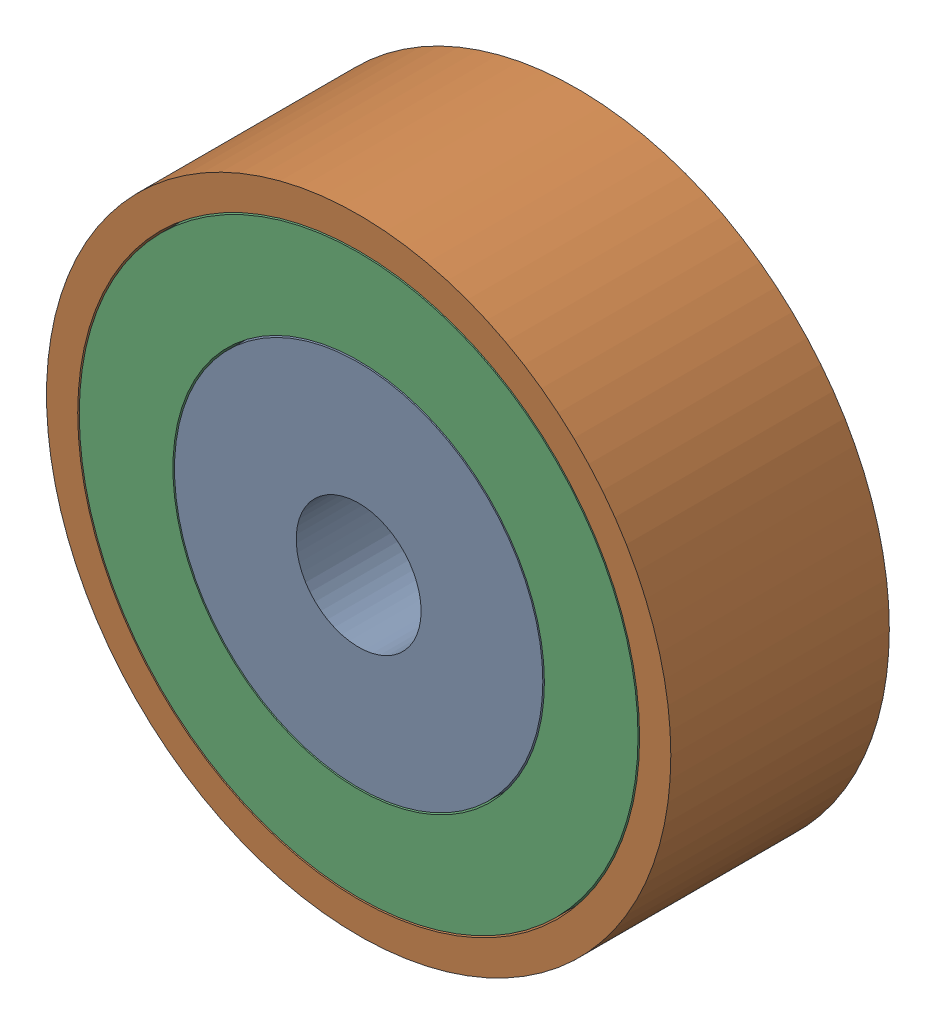
SolidWorks assembly 镜向轴承13, configuration 默认. Lengths in mm.
Overall size (20 20 7).
3 component instances, 3 part files, 4 mates.
Components (placement in the parent):
- 镜向轴承内圈-1: 镜向轴承内圈 [默认] at (-5.0655 0.8032 -6.5) size (11.8 11.8 7)
- 镜向轴承外圈-1: 镜向轴承外圈 [默认] at (-5.0655 0.8032 -6.5) size (20 20 7)
- 镜向轴承中圈-1: 镜向轴承中圈 [默认] at (-5.0655 0.8032 -6.5) size (17.9 17.9 7)
Mates (geometry in assembly coordinates):
- 重合1: coincident: plane of ? through (-5.0655 0.8032 -13.5) normal (0 0 -1); plane of ? through (-5.0655 0.8032 -13.5) normal (0 0 -1)
- 重合2: coincident: plane of ? through (-5.0655 0.8032 -13.5) normal (0 0 -1); plane of ? through (-5.0655 0.8032 -13.5) normal (0 0 -1)
- 同心1: concentric: cylinder of ? through (-5.0655 0.8032 -13.5) axis (0 0 1) radius 9; cylinder of ? through (-5.0655 0.8032 -13.5) axis (0 0 1) radius 8.95
- 同心2: concentric: cylinder of ? through (-5.0655 0.8032 -13.5) axis (0 0 1) radius 5.9; cylinder of ? through (-5.0655 0.8032 -13.5) axis (0 0 1) radius 5.95
